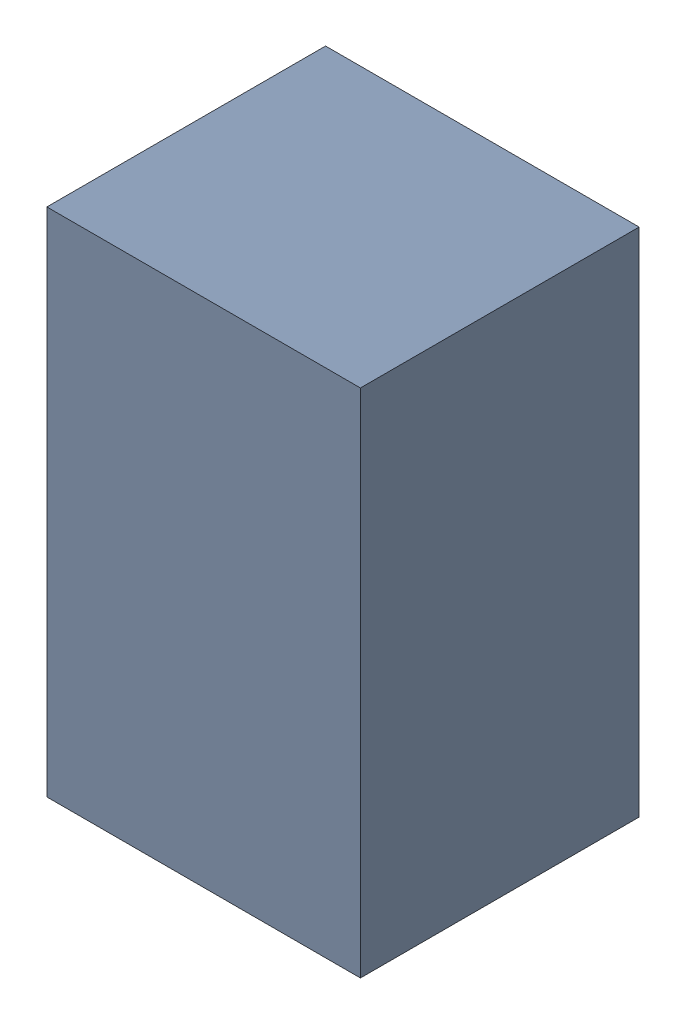
SolidWorks assembly C8, configuration Default. Lengths in mm.
Overall size (1.35 2.2 1.2).
2 component instances, 1 part files, 0 mates.
Components (placement in the parent):
- 407985568-1: 407985568 [Default] at (16.637 43.307 0.0127) size (1.35 2.2 1.2)
  - Extruded_3-1: Extruded_3 [Default] at origin size (1.35 2.2 1.2)
